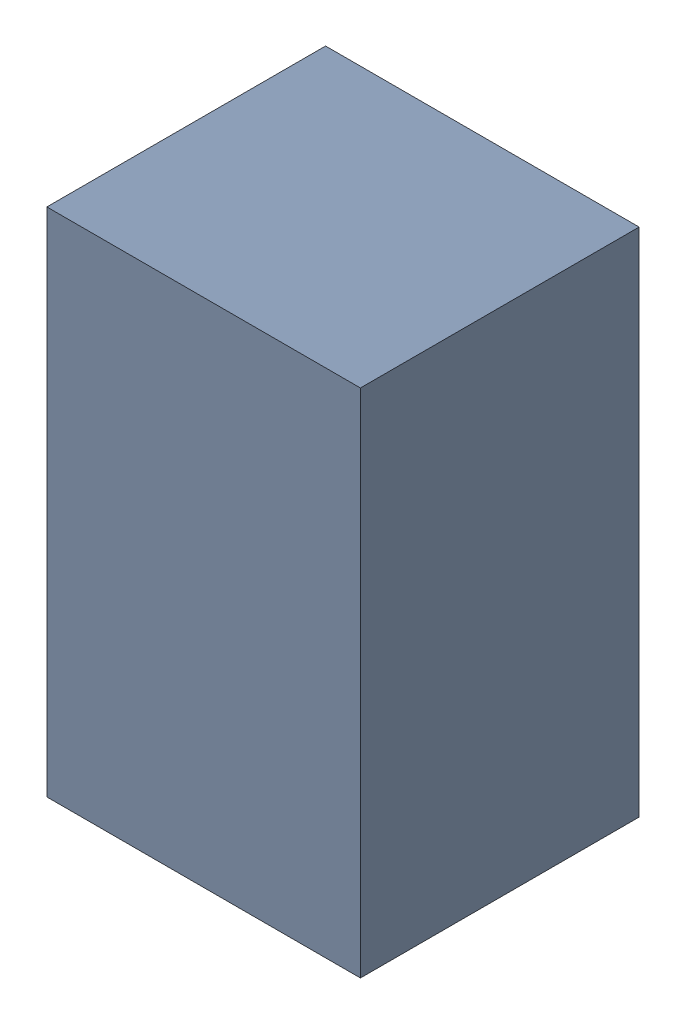
SolidWorks assembly CP1, configuration Default. Lengths in mm.
Overall size (1.35 2.2 1.2).
2 component instances, 1 part files, 0 mates.
Components (placement in the parent):
- 407985568-1: 407985568 [Default] at (74.4982 65.532 -1.6039) size (1.35 2.2 1.2)
  - Extruded_3-1: Extruded_3 [Default] at origin size (1.35 2.2 1.2)
